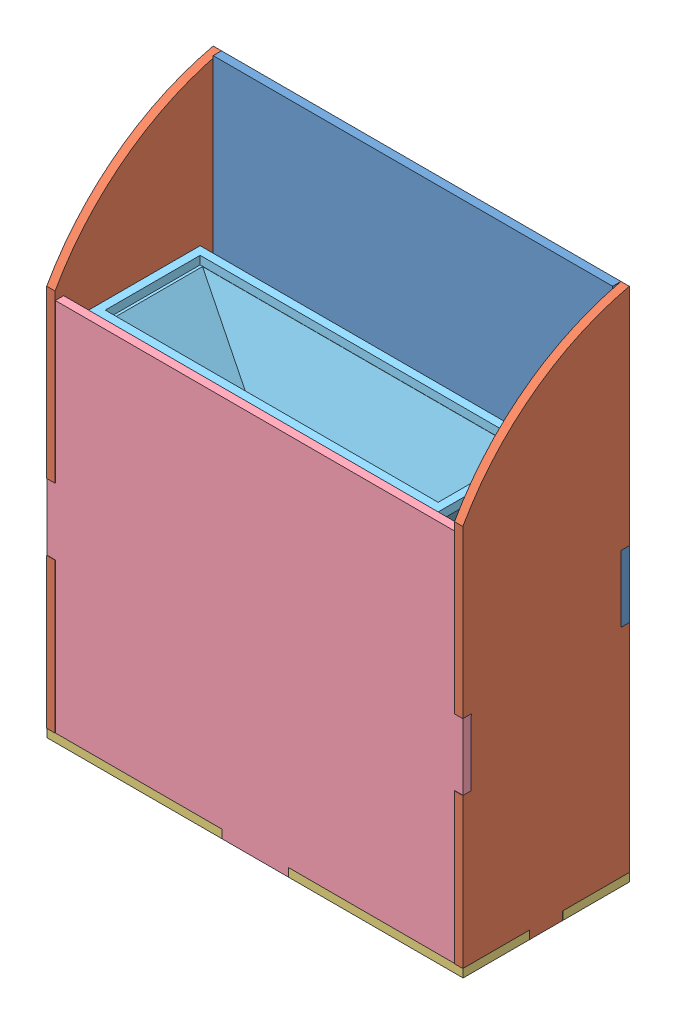
SolidWorks assembly PanierDecoup, configuration Défaut. Lengths in mm.
Overall size (250 310 100).
8 component instances, 7 part files, 20 mates.
Components (placement in the parent):
- BackP-1: BackP [Défaut] at (-218.9712 131.24 380) size (250 310 5)
- JnabP-1: JnabP [Défaut] at (-218.9712 -304.4673 480) x (0 0 -1) z (1 0 0) size (100 310 5)
- JnabP-2: JnabP [Défaut] at (26.0288 -304.4673 480) x (0 0 -1) z (1 0 0) size (100 310 5)
- BaseP-1: BaseP [Défaut] at (-218.9712 -158.76 462.3799) x (1 0 0) z (0 -1 0) size (250 99.82 5)
- FaceP-2: FaceP [Défaut] at (-218.9712 157.7597 474.8192) size (250 230 5)
- 9ma3-1: 9ma3 [Défaut] at (-193.9712 66.24 479.639) x (1 0 0) z (0 -1 0) size (210 67 105)
- Tube-1: Tube [Défaut] at (-93.9712 -38.76 452.8192) x (1 0 0) z (0 -1 0) size (30 30 50)
- Infrared Sensor-1: Infrared Sensor [Default] at (-93.9712 -78.3235 474.8192) x (1 0 0) z (0 1 0) size (14.5 8.55 44.7)
Mates (geometry in assembly coordinates):
- Coïncidente1: coincident aligned: plane of BackP-1 through (-218.9712 131.24 380) normal (0 0 -1); plane of JnabP-1 through (-213.9712 11.24 380) normal (0 0 -1)
- Coïncidente2: coincident aligned: plane of BackP-1 through (-218.9712 131.24 380) normal (0 0 -1); plane of JnabP-1 through (-213.9712 11.24 380) normal (0 0 -1)
- Parallèle1: parallel aligned: plane of BackP-1 through (-213.9712 146.24 385) normal (-1 0 0); plane of JnabP-1 through (-218.9712 -4.2844 345.2317) normal (-1 0 0)
- Coïncidente4: coincident aligned: plane of BackP-1 through (-218.9712 11.24 385) normal (-1 0 0); plane of JnabP-1 through (-218.9712 -4.2844 345.2317) normal (-1 0 0)
- Coïncidente9: coincident aligned: plane of JnabP-1 through (-213.9712 -163.76 440) normal (0 -1 0); plane of BaseP-1 through (-218.9712 -163.76 462.3799) normal (0 -1 0)
- Coïncidente12: coincident aligned: line of BackP-1 through (26.0288 146.24 380) axis (-1 0 0); line of JnabP-2 through (31.0288 146.24 380) axis (-1 0 0)
- Coïncidente13: coincident aligned: plane of BackP-1 through (-113.9712 -163.76 385) normal (0 -1 0); plane of BaseP-1 through (-218.9712 -163.76 462.3799) normal (0 -1 0)
- Coïncidente14: coincident aligned: plane of BackP-1 through (-218.9712 131.24 380) normal (0 0 -1); plane of BaseP-1 through (-73.9712 -163.76 380) normal (0 0 -1)
- Coïncidente15: coincident aligned: plane of JnabP-2 through (31.0288 -4.2844 345.2317) normal (1 0 0); plane of BaseP-1 through (31.0288 -163.76 419.8192) normal (1 0 0)
- Coïncidente17: coincident aligned: plane of BaseP-1 through (-73.9712 -163.76 479.8192) normal (0 0 1); plane of FaceP-2 through (-218.9712 157.7597 479.8192) normal (0 0 1)
- Coïncidente18: coincident anti-aligned: plane of JnabP-1 through (-213.9712 -4.2844 345.2317) normal (1 0 0); plane of FaceP-2 through (-213.9712 -68.76 479.8192) normal (-1 0 0)
- Coïncidente19: coincident aligned: plane of BaseP-1 through (-218.9712 -163.76 462.3799) normal (0 -1 0); plane of FaceP-2 through (-113.9712 -163.76 479.8192) normal (0 -1 0)
- Largeur1: width aligned: plane of JnabP-1 through (-218.9712 -4.2844 345.2317) normal (-1 0 0); plane of JnabP-2 through (31.0288 -4.2844 345.2317) normal (1 0 0); plane of 9ma3-1 through (-198.9712 61.24 497.8192) normal (-1 0 0); plane of 9ma3-1 through (11.0288 61.24 497.8192) normal (1 0 0)
- Coïncidente21: coincident aligned: plane of FaceP-2 through (-213.9712 66.24 479.8192) normal (0 1 0); plane of 9ma3-1 through (-193.9712 66.24 479.639) normal (0 1 0)
- Coaxiale1: concentric anti-aligned: circle of 9ma3-1; cylinder of Tube-1 through (-93.9712 -88.76 452.8192) axis (0 1 0) radius 15
- Coïncidente22: coincident anti-aligned: plane of 9ma3-1 through (-193.9712 -38.76 497.8192) normal (0 -1 0); plane of Tube-1 through (-93.9712 -38.76 452.8192) normal (0 1 0)
- Coïncidente23: coincident anti-aligned: plane of FaceP-2 through (-218.9712 157.7597 474.8192) normal (0 0 -1); plane of 9ma3-1 through (-193.9712 66.24 474.8192) normal (0 0 1)
- Largeur2: width: plane of FaceP-2 through (31.0288 -28.76 479.8192) normal (1 0 0); plane of FaceP-2 through (-218.9712 -28.76 479.8192) normal (-1 0 0); plane of Infrared Sensor-1 through (-101.2212 -94.0735 472.8192) normal (-1 0 0); plane of Infrared Sensor-1 through (-86.7212 -94.0735 472.8192) normal (1 0 0)
- Coïncidente24: coincident: plane of FaceP-2 through (-218.9712 157.7597 474.8192) normal (0 0 -1); plane of Infrared Sensor-1 through (-93.9712 -78.3235 474.8192) normal (0 0 1)
- Verrouiller1: lock: 
